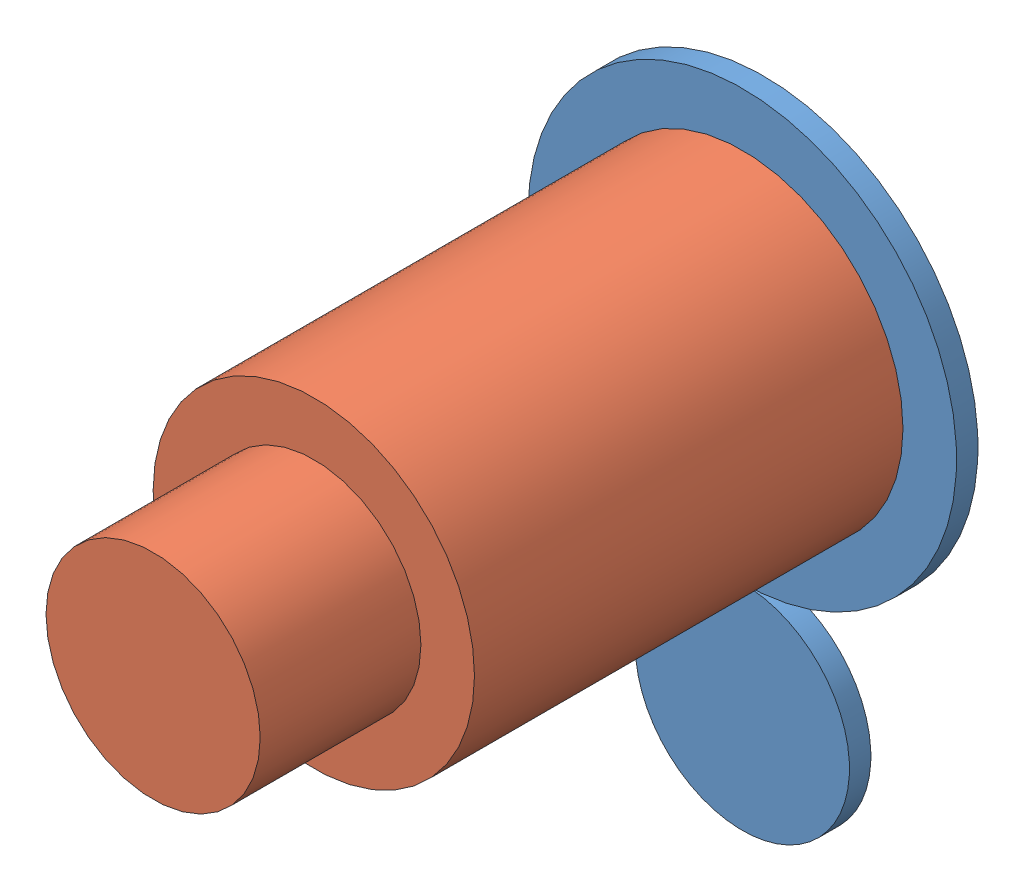
SolidWorks assembly 004-Git Hub test ASY.2, configuration Default. Lengths in mm.
Overall size (50.8 76.2 72.39).
2 component instances, 2 part files, 3 mates.
Components (placement in the parent):
- 002-Github test base-1: 002-Github test base [Default] at origin size (50.8 76.2 2.54)
- 003-Github test top-1: 003-Github test top [Default] at (0 0 2.54) size (50.8 76.2 69.85)
Mates (geometry in assembly coordinates):
- Coincident1: coincident anti-aligned: plane of 002-Github test base-1 through (0 0 2.54) normal (0 0 1); plane of 003-Github test top-1 through (0 38.1 2.54) normal (0 0 -1)
- Coincident2: coincident aligned: circle of 002-Github test base-1; circle of 003-Github test top-1
- Concentric1: concentric aligned: circle of 002-Github test base-1; circle of 003-Github test top-1
